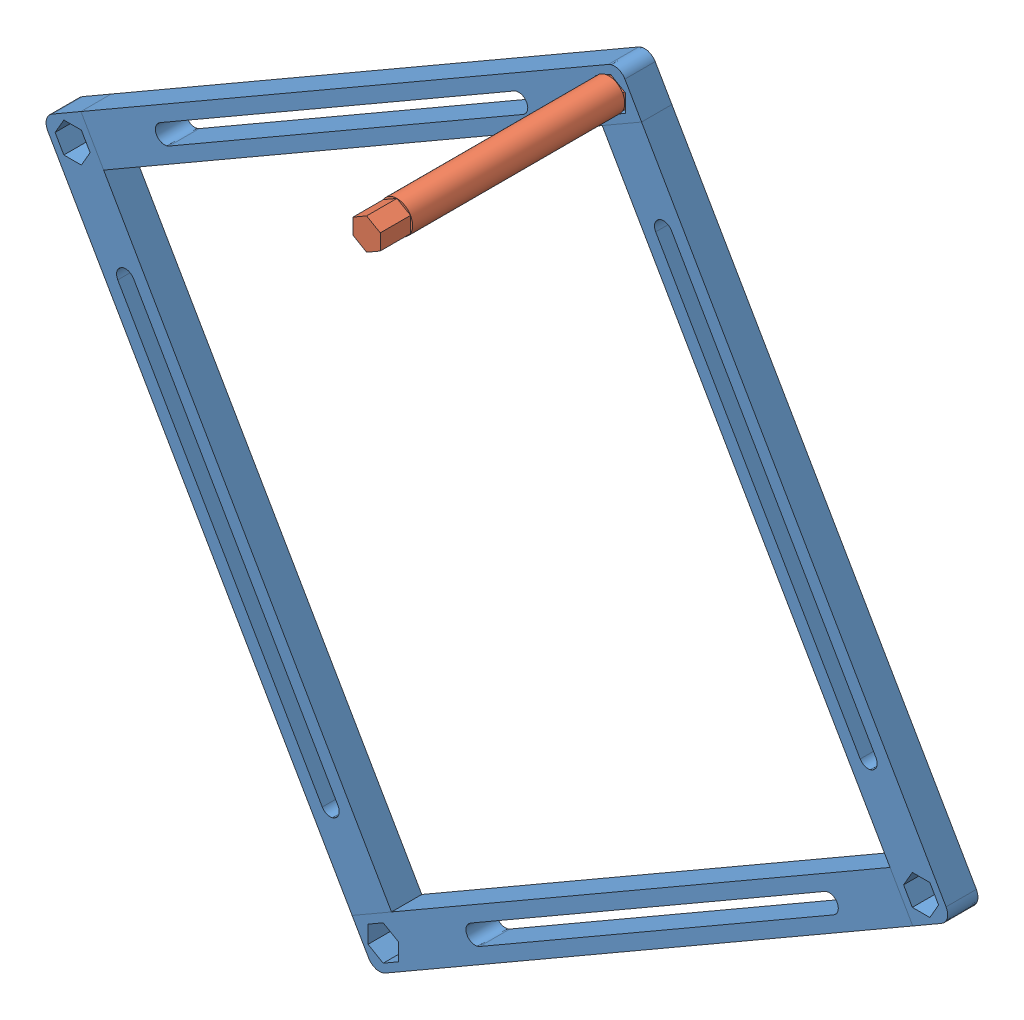
SolidWorks assembly SoporteCaja, configuration Predeterminado. Lengths in mm.
Overall size (300.53 300.53 90).
6 component instances, 2 part files, 2 mates.
Components (placement in the parent):
- Ensamblaje2^SoporteCaja-1: Ensamblaje2^SoporteCaja [Predeterminado] at (-108.0323 -26.3107 -1.6841) x (0.5 -0.866025 0) z (0 0 1) size (220 220 10) (virtual)
  - EstructuraCajasTela-1: EstructuraCajasTela [Predeterminado] at (-79.0714 94.07 205) size (20 205 10)
  - EstructuraCajasTela-2: EstructuraCajasTela [Predeterminado] at (140.9286 94.07 205) x (0 -1 0) z (0 0 1) size (20 205 10)
  - EstructuraCajasTela-3: EstructuraCajasTela [Predeterminado] at (-79.0714 -125.93 205) x (0 1 0) z (0 0 1) size (20 205 10)
  - EstructuraCajasTela-4: EstructuraCajasTela [Predeterminado] at (140.9286 -125.93 205) x (-1 0 0) z (0 0 1) size (20 205 10)
- PilarEstructuraCajas-1: PilarEstructuraCajas [Predeterminado] at (-69.3462 78.8139 203.3159) size (10.39 10.39 90)
Mates (geometry in assembly coordinates):
- Coincidente12: coincident anti-aligned: plane of Ensamblaje2^Ensamblaje1-1/EstructuraCajasTela-1 through (-66.101 89.2021 213.3159) normal (0 0 1); plane of PilarEstructuraCajas-1 through (-69.3462 78.8139 213.3159) normal (0 0 -1)
- Coincidente13: coincident anti-aligned: plane of Ensamblaje2^Ensamblaje1-1/EstructuraCajasTela-1 through (-73.8462 81.8437 213.3159) normal (1 0 0); plane of PilarEstructuraCajas-1 through (-73.8462 81.4119 213.3159) normal (-1 0 0)
